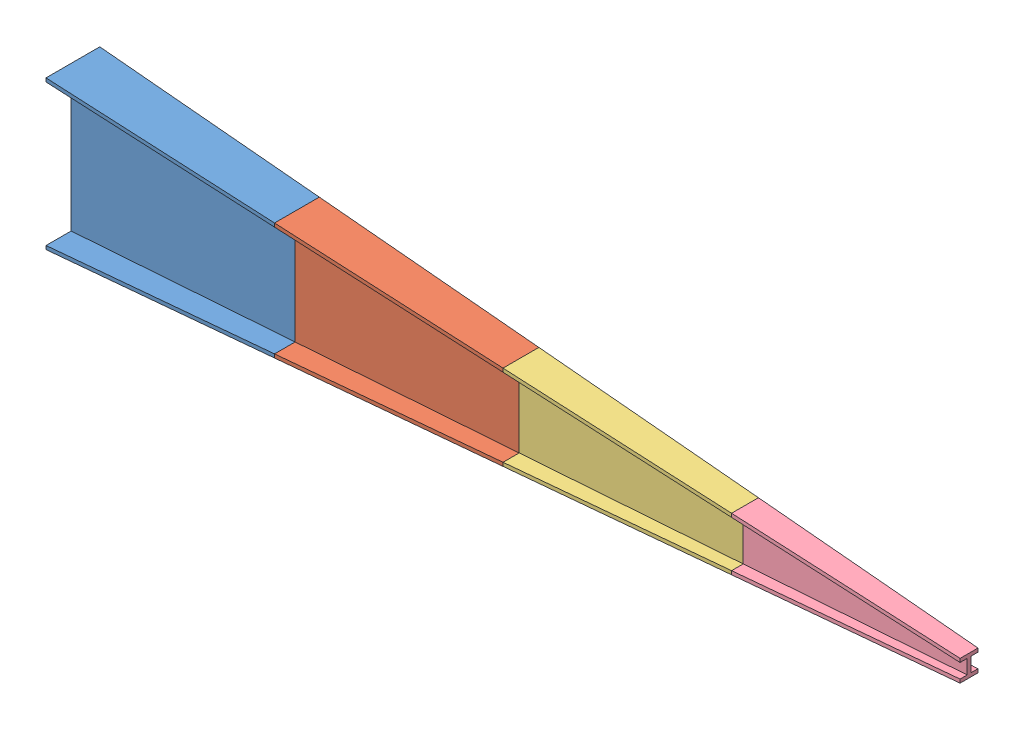
SolidWorks assembly Assembly, configuration Default. Lengths in mm.
Overall size (5000 830 300).
4 component instances, 4 part files, 9 mates.
Components (placement in the parent):
- 1-1: 1 [Default] at (-775.9263 612.0858 1043.8579) size (1250 830 300)
- 2-2: 2 [Default] at (474.0737 612.0858 1043.8579) size (1250 652.5 250)
- 3-2: 3 [Default] at (1724.0737 612.0858 1043.8579) size (1250 475 200)
- 4-2: 4 [Default] at (2974.0737 612.0858 1043.8579) size (1250 297.5 150)
Mates (geometry in assembly coordinates):
- Coincident39: coincident anti-aligned: plane of 1-1 through (474.0737 612.0858 1043.8579) normal (1 0 0); plane of 2-2 through (474.0737 612.0858 1043.8579) normal (-1 0 0)
- Coincident40: coincident anti-aligned: plane of 2-2 through (1724.0737 612.0858 1043.8579) normal (1 0 0); plane of 3-2 through (1724.0737 612.0858 1043.8579) normal (-1 0 0)
- Coincident42: coincident: point of 1-1; point of 2-2
- Coincident43: coincident: point of 1-1; point of 2-2
- Coincident44: coincident: point of 2-2; point of 3-2
- Coincident46: coincident: point of 2-2; point of 3-2
- Coincident49: coincident: point of 3-2; point of 4-2
- Coincident52: coincident aligned: plane of 3-2 through (1724.0737 612.0858 1063.8579) normal (0 0 1); plane of 4-2 through (2974.0737 612.0858 1063.8579) normal (0 0 1)
- Coincident53: coincident: point of 3-2; point of 4-2
